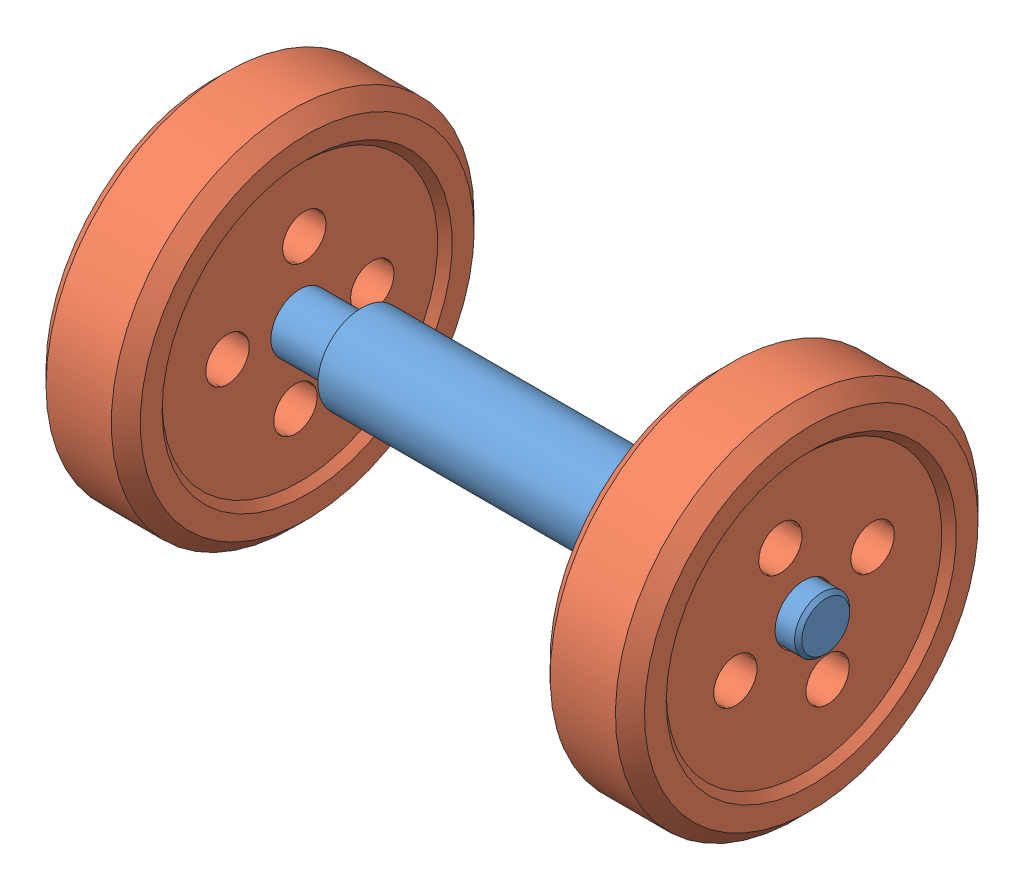
SolidWorks assembly front assmbly, configuration Default. Lengths in mm.
Overall size (844.88 635.56 635.56).
3 component instances, 2 part files, 3 mates.
Components (placement in the parent):
- Part2-1: Part2 [Default] at (292.0461 432.0687 660.3918) size (840 120 120)
- wheel + tire-1: wheel + tire [Default] at (627.0952 432.0687 660.3918) x (0 -0.325618 0.945501) z (-1 0 0) size (500 500 130)
- wheel + tire-2: wheel + tire [Default] at (-67.832 432.0687 660.3918) x (0 -0.060971 -0.99814) z (1 0 0) size (500 500 130)
Mates (geometry in assembly coordinates):
- Concentric1: concentric anti-aligned: cylinder of Part2-1 through (712.0461 432.0687 660.3918) axis (-1 0 0) radius 38; cylinder of wheel + tire-1 through (562.0952 432.0687 660.3918) axis (1 0 0) radius 40
- Coincident1: coincident aligned: cylinder of Part2-1 through (602.0461 432.0687 660.3918) axis (-1 0 0) radius 40; circle of wheel + tire-1
- Concentric3: concentric anti-aligned: cylinder of Part2-1 through (-17.9539 432.0687 660.3918) axis (1 0 0) radius 40; cylinder of wheel + tire-2 through (-2.832 432.0687 660.3918) axis (-1 0 0) radius 40
